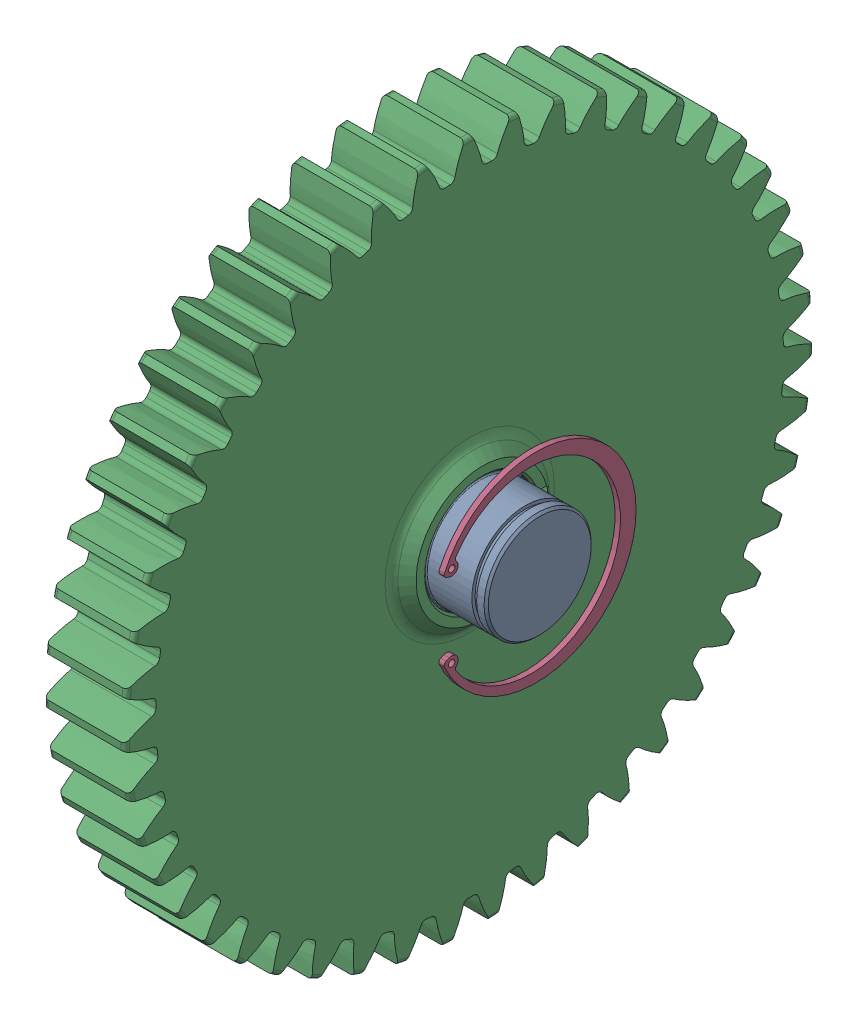
SolidWorks assembly g1_3_1_1_3_1, configuration 默认. Lengths in mm.
Overall size (103.5 321.87 322.01).
4 component instances, 4 part files, 0 mates.
Components (placement in the parent):
- g1_3_1_1_3-1_1-1: g1_3_1_1_3-1_1 [默认] at origin size (103.5 52 52)
- 16x10x45_gb1096_1-1: 16x10x45_gb1096_1 [默认] at (-0.5 0 25) x (1 0 0) z (0 0 -1) size (45 16 10)
- _X2_60F08F6E_X0_g1_3_1_1_3-2_1-1: _X2_60F08F6E_X0_g1_3_1_1_3-2_1 [默认] at (25 0 0) x (0 0 1) z (1 0 0) size (322.01 321.87 50.08)
- 90_gb893_1_1-1: 90_gb893_1_1 [默认] at (45.05 0 -2.4333) x (0 1 0) z (1 0 0) size (93.5 89.63 2.5)
